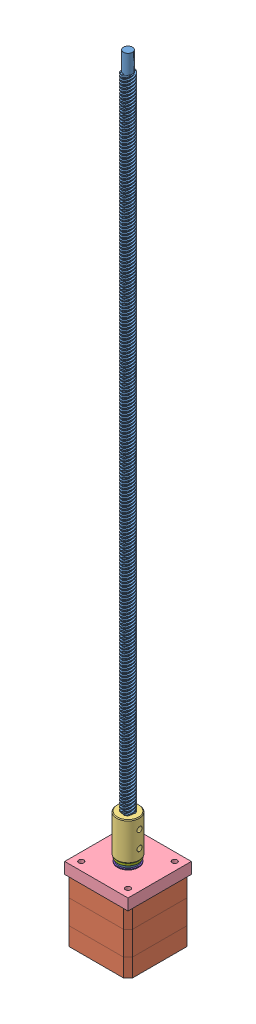
SolidWorks assembly Lead Screw Stepper Subassembly, configuration Default. Lengths in mm.
Overall size (42 514 42).
16 component instances, 8 part files, 9 mates.
Components (placement in the parent):
- Lead Screw-1: Lead Screw [Default] at (-91.1951 101.7497 -17.5984) x (0.863465 0 -0.504409) z (-0.504409 0 -0.863465) size (8.59 449 8.59)
- Stepper Model-1: Stepper Model [Default] at (-91.1951 37.7497 -17.5984) size (42 64 42)
- Lead Screw-Stepper Coupler-1: Lead Screw-Stepper Coupler [Default] at (-91.1951 89.2497 -17.5984) x (-0.047448 0 -0.998874) z (0.998874 0 -0.047448) size (15 25 15)
- Thrust Bearing Seat-1: Thrust Bearing Seat [Default] at (-91.1951 77.7497 -17.5984) size (42 7.5 42)
- 1613-0514-0006-1: 1613-0514-0006 [Default] at (-105.3171 88.3186 -40.963) x (-0.837169 0 -0.546944) z (-0.546944 0 0.837169) size (18.78 4.84 18.78)
  - 1613-0514-0006 carriage.STEP-1: 1613-0514-0006 carriage.STEP [Default] at (-24.6017 0.9565 11.8362) size (12.8 1.46 12.8)
  - 1613-0514-0006 ball.STEP-1: 1613-0514-0006 ball.STEP [Default] at (-29.5231 1.6489 11.0748) size (2.37 2.37 2.37)
  - 1613-0514-0006 ball.STEP-2: 1613-0514-0006 ball.STEP [Default] at (-27.5433 1.6489 7.8178) x (0.707107 0 0.707107) z (-0.707107 0 0.707107) size (2.37 2.37 2.37)
  - 1613-0514-0006 ball.STEP-3: 1613-0514-0006 ball.STEP [Default] at (-23.8403 1.6489 6.9147) x (0 0 1) z (-1 0 0) size (2.37 2.37 2.37)
  - 1613-0514-0006 ball.STEP-4: 1613-0514-0006 ball.STEP [Default] at (-20.5833 1.6489 8.8946) x (-0.707107 0 0.707107) z (-0.707107 0 -0.707107) size (2.37 2.37 2.37)
  - 1613-0514-0006 ball.STEP-5: 1613-0514-0006 ball.STEP [Default] at (-19.6802 1.6489 12.5976) x (-1 0 0) z (0 0 -1) size (2.37 2.37 2.37)
  - 1613-0514-0006 ball.STEP-6: 1613-0514-0006 ball.STEP [Default] at (-21.6601 1.6489 15.8546) x (-0.707107 0 -0.707107) z (0.707107 0 -0.707107) size (2.37 2.37 2.37)
  - 1613-0514-0006 ball.STEP-7: 1613-0514-0006 ball.STEP [Default] at (-25.3631 1.6489 16.7576) x (0 0 -1) z (1 0 0) size (2.37 2.37 2.37)
  - 1613-0514-0006 ball.STEP-8: 1613-0514-0006 ball.STEP [Default] at (-28.62 1.6489 14.7778) x (0.707107 0 -0.707107) z (0.707107 0 0.707107) size (2.37 2.37 2.37)
  - 1613-0514-0006 washer (6.33mm ID).STEP-1: 1613-0514-0006 washer (6.33mm ID).STEP [Default] at (-24.6017 -0.7711 11.8362) x (0.328148 0 0.944626) z (-0.944626 0 0.328148) size (14 1.5 14)
  - 1613-0514-0006 washer (6mm ID).STEP-1: 1613-0514-0006 washer (6mm ID).STEP [Default] at (-24.6017 4.0689 11.8362) x (-0.894397 0 -0.447274) z (-0.447274 0 0.894397) size (14 1.5 14)
Mates (geometry in assembly coordinates):
- Distance1: distance = 1 mm anti-aligned: plane of Stepper Model-1 through (-91.1951 101.7497 -17.5984) normal (0 1 0); plane of Lead Screw-1 through (-91.1951 102.7497 -17.5984) normal (0 -1 0)
- Concentric4: concentric aligned: cylinder of Lead Screw-1 through (-91.1951 551.7497 -17.5984) axis (0 -1 0) radius 3; cylinder of Lead Screw-Stepper Coupler-1 through (-91.1951 114.2497 -17.5984) axis (0 -1 0) radius 2.5
- Concentric6: concentric aligned: cylinder of Lead Screw-1 through (-91.1951 551.7497 -17.5984) axis (0 -1 0) radius 3; cylinder of Stepper Model-1 through (-91.1951 101.7497 -17.5984) axis (0 -1 0) radius 3
- Coincident7: coincident anti-aligned: plane of Lead Screw-1 through (-89.6819 114.2497 -15.008) normal (0 -1 0); plane of Lead Screw-Stepper Coupler-1 through (-91.1951 114.2497 -17.5984) normal (0 1 0)
- Coincident8: coincident anti-aligned: plane of Stepper Model-1 through (-91.1951 77.7497 -17.5984) normal (0 1 0); plane of Thrust Bearing Seat-1 through (-91.1951 77.7497 -17.5984) normal (0 -1 0)
- Coincident9: coincident aligned: plane of Stepper Model-1 through (-70.1951 77.7497 3.4016) normal (1 0 0); plane of Thrust Bearing Seat-1 through (-70.1951 85.2497 3.4016) normal (1 0 0)
- Coincident10: coincident aligned: plane of Stepper Model-1 through (-112.1951 77.7497 3.4016) normal (0 0 1); plane of Thrust Bearing Seat-1 through (-112.1951 85.2497 3.4016) normal (0 0 1)
- Concentric8: concentric aligned: cylinder of 1613-0514-0006-1/1613-0514-0006 washer (6.33mm ID).STEP-1 through (-91.1951 87.5897 -17.5984) axis (0 1 0) radius 7; cylinder of Thrust Bearing Seat-1 through (-91.1951 84.2497 -17.5984) axis (0 1 0) radius 7
- Coincident11: coincident anti-aligned: plane of Thrust Bearing Seat-1 through (-91.1951 84.2497 -17.5984) normal (0 1 0); plane of 1613-0514-0006-1/1613-0514-0006 washer (6mm ID).STEP-1 through (-91.1951 84.2497 -17.5984) normal (0 -1 0)
